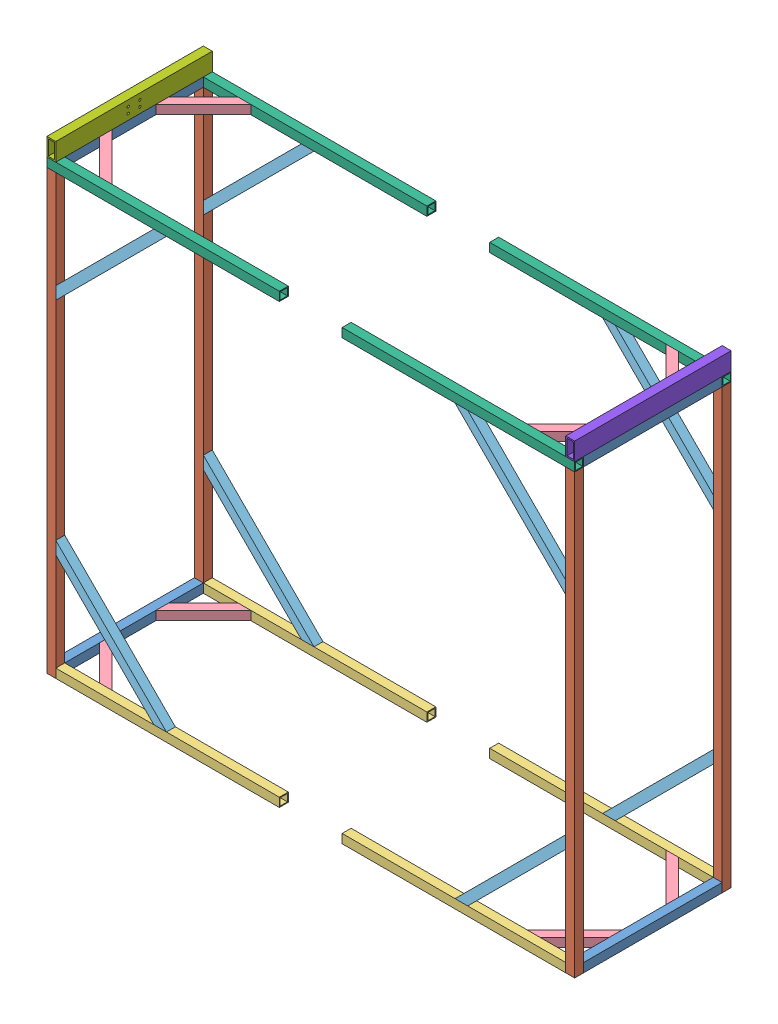
SolidWorks assembly 010114_frame_connection, configuration Default. Lengths in mm.
Overall size (2361 2080 708).
44 component instances, 9 part files, 19 mates.
Components (placement in the parent):
- 010112_frame_half-1: 010112_frame_half [Default] at origin size (1040 2000 700)
  - 010101_ST_40x4x620-1: 010101_ST_40x4x620 [Default] at origin size (40 40 620)
  - 010102_ST_40x4x1960-1: 010102_ST_40x4x1960 [Default] at (0 -20 640) x (0 0 -1) z (0 1 0) size (40 40 1960)
  - 010105_ST_40x4x1000-1: 010105_ST_40x4x1000 [Default] at (520 0 640) x (0 0 1) z (-1 0 0) size (40 40 1000)
  - 010109_ST_40x4x300_chamfered-1: 010109_ST_40x4x300_chamfered [Default] at (5.8579 0 422.0101) x (0.707107 0 -0.707107) z (0.707107 0 0.707107) size (40 40 300)
  - 010106_ST_40x4x700_chamfered-1: 010106_ST_40x4x700_chamfered [Default] at (500.8326 5.8579 640) x (0.707107 0.707107 0) z (-0.707107 0.707107 0) size (40 40 700)
  - 010108_ST_40x4x1040-1: 010108_ST_40x4x1040 [Default] at (500 1960 640) x (0 0 1) z (-1 0 0) size (40 40 1040)
  - 010101_ST_40x4x620-2: 010101_ST_40x4x620 [Default] at (0 1960 620) x (1 0 0) z (0 0 -1) size (40 40 620)
  - 010106_ST_40x4x700_chamfered-2: 010106_ST_40x4x700_chamfered [Default] at (5.8579 1459.1674 640) x (0.707107 -0.707107 0) z (0.707107 0.707107 0) size (40 40 700)
  - 010109_ST_40x4x300_chamfered-2: 010109_ST_40x4x300_chamfered [Default] at (217.9899 1960 634.1421) x (0.707107 0 -0.707107) z (-0.707107 0 -0.707107) size (40 40 300)
  - 010101_ST_40x4x620-3: 010101_ST_40x4x620 [Default] at (0 1960 620) x (1 0 0) z (0 0 -1) size (40 40 620)
  - 010109_ST_40x4x300_chamfered-3: 010109_ST_40x4x300_chamfered [Default] at (5.8579 1960 197.9899) x (0.707107 0 0.707107) z (0.707107 0 -0.707107) size (40 40 300)
  - 010106_ST_40x4x700_chamfered-3: 010106_ST_40x4x700_chamfered [Default] at (500.8326 1954.1421 -20) x (0.707107 -0.707107 0) z (-0.707107 -0.707107 0) size (40 40 700)
  - 010106_ST_40x4x700_chamfered-4: 010106_ST_40x4x700_chamfered [Default] at (5.8579 500.8326 -20) x (0.707107 0.707107 0) z (0.707107 -0.707107 0) size (40 40 700)
  - 010108_ST_40x4x1040-2: 010108_ST_40x4x1040 [Default] at (500 1960 -20) x (0 0 -1) z (1 0 0) size (40 40 1040)
  - 010105_ST_40x4x1000-2: 010105_ST_40x4x1000 [Default] at (520 0 -20) x (0 0 -1) z (1 0 0) size (40 40 1000)
  - 010109_ST_40x4x300_chamfered-4: 010109_ST_40x4x300_chamfered [Default] at (217.9899 0 -14.1421) x (0.707107 0 0.707107) z (-0.707107 0 0.707107) size (40 40 300)
  - 010102_ST_40x4x1960-2: 010102_ST_40x4x1960 [Default] at (0 1940 -20) x (0 0 1) z (0 -1 0) size (40 40 1960)
- 010112_frame_half-2: 010112_frame_half [Default] at (2321 0 620) x (-1 0 0) z (0 0 -1) size (1040 2000 700)
  - 010101_ST_40x4x620-1: 010101_ST_40x4x620 [Default] at origin size (40 40 620)
  - 010102_ST_40x4x1960-1: 010102_ST_40x4x1960 [Default] at (0 -20 640) x (0 0 -1) z (0 1 0) size (40 40 1960)
  - 010105_ST_40x4x1000-1: 010105_ST_40x4x1000 [Default] at (520 0 640) x (0 0 1) z (-1 0 0) size (40 40 1000)
  - 010109_ST_40x4x300_chamfered-1: 010109_ST_40x4x300_chamfered [Default] at (5.8579 0 422.0101) x (0.707107 0 -0.707107) z (0.707107 0 0.707107) size (40 40 300)
  - 010106_ST_40x4x700_chamfered-1: 010106_ST_40x4x700_chamfered [Default] at (500.8326 5.8579 640) x (0.707107 0.707107 0) z (-0.707107 0.707107 0) size (40 40 700)
  - 010108_ST_40x4x1040-1: 010108_ST_40x4x1040 [Default] at (500 1960 640) x (0 0 1) z (-1 0 0) size (40 40 1040)
  - 010101_ST_40x4x620-2: 010101_ST_40x4x620 [Default] at (0 1960 620) x (1 0 0) z (0 0 -1) size (40 40 620)
  - 010106_ST_40x4x700_chamfered-2: 010106_ST_40x4x700_chamfered [Default] at (5.8579 1459.1674 640) x (0.707107 -0.707107 0) z (0.707107 0.707107 0) size (40 40 700)
  - 010109_ST_40x4x300_chamfered-2: 010109_ST_40x4x300_chamfered [Default] at (217.9899 1960 634.1421) x (0.707107 0 -0.707107) z (-0.707107 0 -0.707107) size (40 40 300)
  - 010101_ST_40x4x620-3: 010101_ST_40x4x620 [Default] at (0 1960 620) x (1 0 0) z (0 0 -1) size (40 40 620)
  - 010109_ST_40x4x300_chamfered-3: 010109_ST_40x4x300_chamfered [Default] at (5.8579 1960 197.9899) x (0.707107 0 0.707107) z (0.707107 0 -0.707107) size (40 40 300)
  - 010106_ST_40x4x700_chamfered-3: 010106_ST_40x4x700_chamfered [Default] at (500.8326 1954.1421 -20) x (0.707107 -0.707107 0) z (-0.707107 -0.707107 0) size (40 40 700)
  - 010106_ST_40x4x700_chamfered-4: 010106_ST_40x4x700_chamfered [Default] at (5.8579 500.8326 -20) x (0.707107 0.707107 0) z (0.707107 -0.707107 0) size (40 40 700)
  - 010108_ST_40x4x1040-2: 010108_ST_40x4x1040 [Default] at (500 1960 -20) x (0 0 -1) z (1 0 0) size (40 40 1040)
  - 010105_ST_40x4x1000-2: 010105_ST_40x4x1000 [Default] at (520 0 -20) x (0 0 -1) z (1 0 0) size (40 40 1000)
  - 010109_ST_40x4x300_chamfered-4: 010109_ST_40x4x300_chamfered [Default] at (217.9899 0 -14.1421) x (0.707107 0 0.707107) z (-0.707107 0 0.707107) size (40 40 300)
  - 010102_ST_40x4x1960-2: 010102_ST_40x4x1960 [Default] at (0 1940 -20) x (0 0 1) z (0 -1 0) size (40 40 1960)
- 010113_L_40x4x500-1: 010113_L_40x4x500 [Default] at (1410.5 1944 -44) x (0 0 1) z (-1 0 0) size (40 40 500)
- 010113_L_40x4x500-2: 010113_L_40x4x500 [Default] at (910.5 1944 664) x (0 0 -1) z (1 0 0) size (40 40 500)
- 010113_L_40x4x500-3: 010113_L_40x4x500 [Default] at (1410.5 1936 656) x (0 1 0) z (-1 0 0) size (40 40 500)
- 010113_L_40x4x500-4: 010113_L_40x4x500 [Default] at (910.5 1936 -36) x (0 1 0) z (1 0 0) size (40 40 500)
- 010113_L_40x4x500-5: 010113_L_40x4x500 [Default] at (910.5 24 -4) x (0 -1 0) z (1 0 0) size (40 40 500)
- 010113_L_40x4x500-6: 010113_L_40x4x500 [Default] at (1410.5 24 624) x (0 -1 0) z (-1 0 0) size (40 40 500)
- 010110_RT_80x40x6.3x700_drilled-1: 010110_RT_80x40x6.3x700_drilled [Default] at (0 2020 310) size (40 80 700)
- 010111_RT_80x40x6.3x700-1: 010111_RT_80x40x6.3x700 [Default] at (2321 2020 310) size (40 80 700)
Mates (geometry in assembly coordinates):
- Coincident1: coordinate: point of 010112_frame_half-1
- Coincident2: coincident aligned: plane of 010112_frame_half-1/010108_ST_40x4x1040-1 through (-20 1980 660) normal (0 0 1); plane of 010112_frame_half-2/010108_ST_40x4x1040-2 through (1301 1980 660) normal (0 0 1)
- Coincident3: coincident aligned: plane of 010112_frame_half-1/010108_ST_40x4x1040-1 through (-20 1980 620) normal (0 1 0); plane of 010112_frame_half-2/010108_ST_40x4x1040-2 through (1301 1980 620) normal (0 1 0)
- Distance1: distance = 281 mm anti-aligned: plane of 010112_frame_half-2/010108_ST_40x4x1040-1 through (1301 1960 -20) normal (-1 0 0); plane of 010112_frame_half-1/010108_ST_40x4x1040-2 through (1020 1960 -20) normal (1 0 0)
- Coincident7: coincident anti-aligned: plane of 010112_frame_half-1/010108_ST_40x4x1040-2 through (1020 1980 -40) normal (0 0 -1); plane of 010113_L_40x4x500-1 through (910.5 1980 -40) normal (0 0 1)
- Coincident8: coincident anti-aligned: plane of 010112_frame_half-2/010108_ST_40x4x1040-1 through (2341 1980 0) normal (0 1 0); plane of 010113_L_40x4x500-1 through (910.5 1980 -4) normal (0 -1 0)
- Width1: width aligned: plane of 010113_L_40x4x500-1 through (1410.5 1944 -44) normal (1 0 0); plane of 010112_frame_half-2/010101_ST_40x4x620-2 through (910.5 1944 -44) normal (-1 0 0); plane of 010113_L_40x4x500-1 through (2341 1940 0) normal (1 0 0); plane of 010112_frame_half-1/010101_ST_40x4x620-2 through (-20 1940 620) normal (-1 0 0)
- Coincident9: coincident anti-aligned: plane of 010112_frame_half-1/010108_ST_40x4x1040-1 through (-20 1940 620) normal (0 -1 0); plane of 010113_L_40x4x500-3 through (910.5 1940 620) normal (0 1 0)
- Coincident10: coincident anti-aligned: plane of 010112_frame_half-1/010108_ST_40x4x1040-1 through (-20 1980 620) normal (0 0 -1); plane of 010113_L_40x4x500-3 through (910.5 1976 620) normal (0 0 1)
- Width2: width aligned: plane of 010113_L_40x4x500-3 through (910.5 1936 656) normal (-1 0 0); plane of 010112_frame_half-1/010102_ST_40x4x1960-1 through (1410.5 1936 656) normal (1 0 0); plane of 010113_L_40x4x500-3 through (-20 -20 660) normal (-1 0 0); plane of 010112_frame_half-2/010102_ST_40x4x1960-2 through (2341 1940 660) normal (1 0 0)
- Coincident11: coincident anti-aligned: plane of 010112_frame_half-2/010105_ST_40x4x1000-1 through (2301 20 0) normal (0 1 0); plane of 010113_L_40x4x500-5 through (1410.5 20 -40) normal (0 -1 0)
- Coincident12: coincident anti-aligned: plane of 010112_frame_half-1/010105_ST_40x4x1000-2 through (1020 20 -40) normal (0 0 -1); plane of 010113_L_40x4x500-5 through (1410.5 -16 -40) normal (0 0 1)
- Width3: width anti-aligned: plane of 010113_L_40x4x500-5 through (910.5 24 -4) normal (-1 0 0); plane of 010112_frame_half-2/010101_ST_40x4x620-1 through (1410.5 24 -4) normal (1 0 0); plane of 010113_L_40x4x500-5 through (2341 20 620) normal (1 0 0); plane of 010112_frame_half-1/010101_ST_40x4x620-1 through (-20 20 0) normal (-1 0 0)
- Coincident14: coincident anti-aligned: plane of 010112_frame_half-2/010101_ST_40x4x620-2 through (2341 1980 0) normal (0 1 0); plane of 010110_RT_80x40x6.3x1080_drilled-1 through (-20 1980 660) normal (0 -1 0)
- Width4: width anti-aligned: plane of 010110_RT_80x40x6.3x1080_drilled-1 through (0 2020 -40) normal (0 0 -1); plane of 010112_frame_half-2/010102_ST_40x4x1960-2 through (0 2020 660) normal (0 0 1); plane of 010110_RT_80x40x6.3x1080_drilled-1 through (2341 1940 660) normal (0 0 1); plane of 010112_frame_half-2/010102_ST_40x4x1960-1 through (2341 -20 -40) normal (0 0 -1)
- Coincident15: coincident aligned: plane of 010112_frame_half-1/010101_ST_40x4x620-2 through (-20 1940 620) normal (-1 0 0); plane of 010110_RT_80x40x6.3x1080_drilled-1 through (-20 2060 660) normal (-1 0 0)
- Coincident16: coincident aligned: plane of 010112_frame_half-2/010101_ST_40x4x620-2 through (2341 1940 0) normal (1 0 0); plane of 010111_RT_80x40x6.3x700-1 through (2341 2060 660) normal (1 0 0)
- Coincident17: coincident aligned: plane of 010112_frame_half-2/010108_ST_40x4x1040-1 through (2341 1980 -40) normal (0 0 -1); plane of 010111_RT_80x40x6.3x700-1 through (2321 2020 -40) normal (0 0 -1)
- Coincident18: coincident anti-aligned: plane of 010112_frame_half-2/010101_ST_40x4x620-2 through (2341 1980 0) normal (0 1 0); plane of 010111_RT_80x40x6.3x700-1 through (2301 1980 660) normal (0 -1 0)
